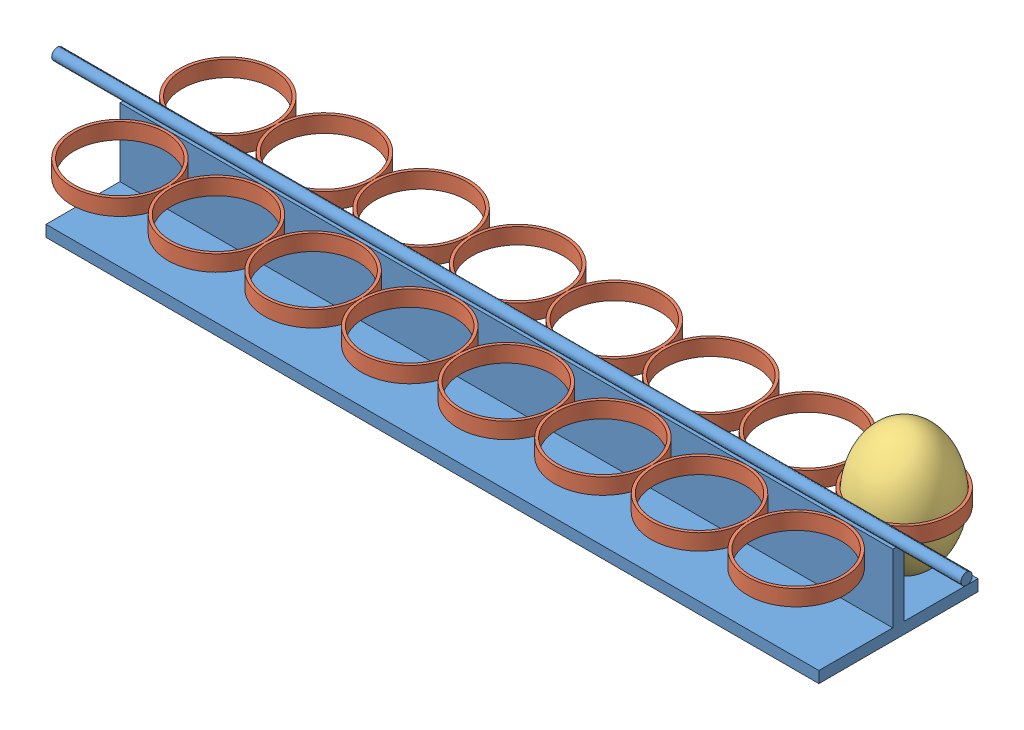
SolidWorks assembly lapghep1dan, configuration Default. Lengths in mm.
Overall size (400 59.31 96.83).
4 component instances, 3 part files, 9 mates.
Components (placement in the parent):
- trucchinh-1: trucchinh [Default] at (130.4073 210.5608 315.7728) size (400 40 70)
- 8oluoi-1: 8oluoi [Default] at (24.8137 68.7344 105.9569) size (340 7 42.5)
- 8oluoi-2: 8oluoi [Default] at (24.8137 68.7344 58.4569) size (340 7 42.5)
- trungga-1: trungga [Default] at (279.1573 237.3745 292.0228) x (0.786877 0 -0.61711) z (0.61711 0 0.786877) size (40 55 40)
Mates (geometry in assembly coordinates):
- Tangent1: tangent aligned: plane of trucchinh-1 through (-39.5927 240.5608 318.2728) normal (-1 0 0); cylinder of 8oluoi-1 through (-18.3427 240.5608 339.5228) axis (0 -1 0) radius 21.25
- Tangent2: tangent anti-aligned: plane of trucchinh-1 through (-39.5927 240.5608 318.2728) normal (0 0 1); cylinder of 8oluoi-1 through (-18.3427 240.5608 339.5228) axis (0 -1 0) radius 21.25
- Tangent4: tangent anti-aligned: plane of trucchinh-1 through (-39.5927 240.5608 318.2728) normal (0 0 1); cylinder of 8oluoi-1 through (279.1573 240.5608 339.5228) axis (0 -1 0) radius 21.25
- Coincident1: coincident aligned: plane of trucchinh-1 through (130.4073 240.5608 315.7728) normal (0 1 0); plane of 8oluoi-1 through (-18.3427 240.5608 339.5228) normal (0 1 0)
- Tangent5: tangent anti-aligned: plane of trucchinh-1 through (-39.5927 240.5608 313.2728) normal (0 0 -1); cylinder of 8oluoi-2 through (-18.3427 240.5608 292.0228) axis (0 -1 0) radius 21.25
- Tangent6: tangent aligned: plane of trucchinh-1 through (-39.5927 240.5608 318.2728) normal (-1 0 0); cylinder of 8oluoi-2 through (-18.3427 240.5608 292.0228) axis (0 -1 0) radius 21.25
- Tangent7: tangent anti-aligned: plane of trucchinh-1 through (-39.5927 240.5608 313.2728) normal (0 0 -1); cylinder of 8oluoi-2 through (279.1573 240.5608 292.0228) axis (0 -1 0) radius 21.25
- Coincident2: coincident aligned: plane of trucchinh-1 through (130.4073 240.5608 315.7728) normal (0 1 0); plane of 8oluoi-2 through (-18.3427 240.5608 292.0228) normal (0 1 0)
- Tangent9: tangent: cylinder of 8oluoi-2 through (279.1573 240.5608 292.0228) axis (0 -1 0) radius 20; face of trungga-1
